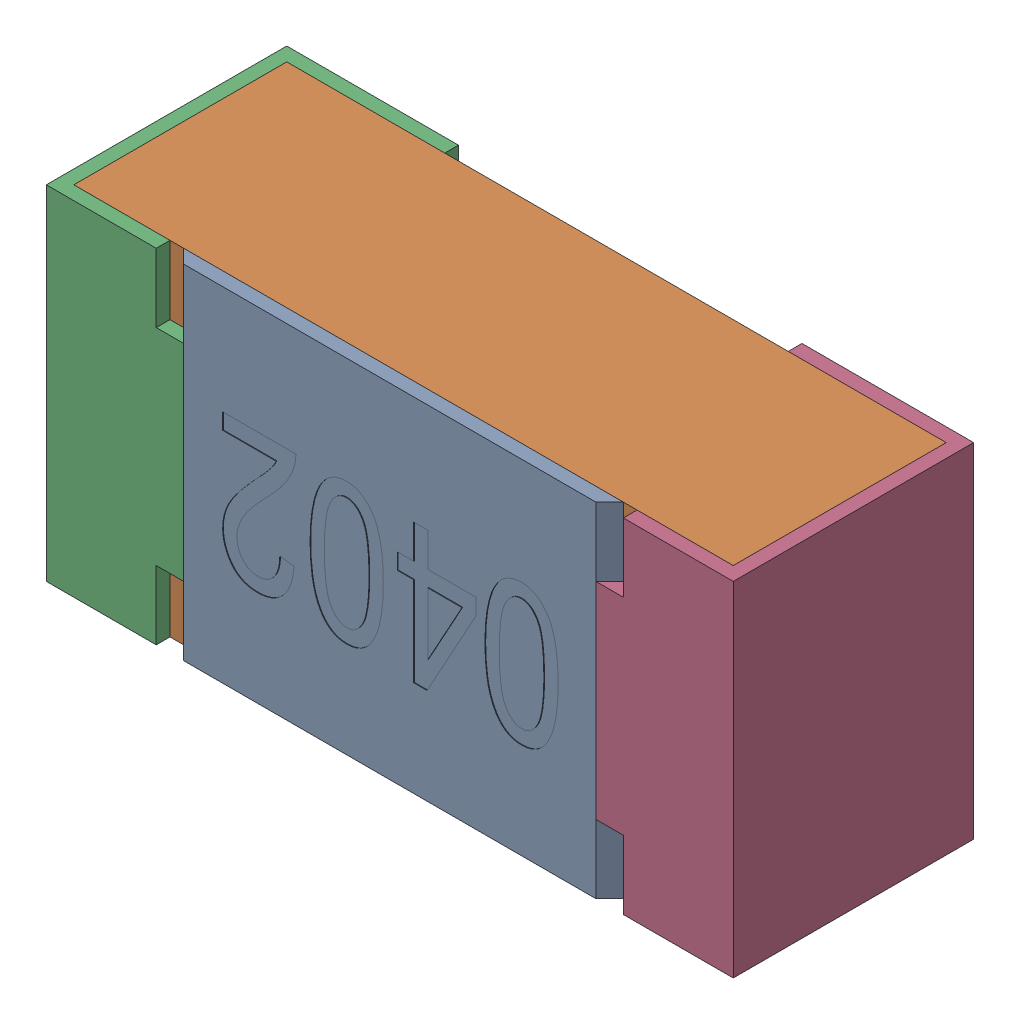
SolidWorks assembly R20, configuration Standard. Lengths in mm.
Overall size (1 0.5 0.35).
5 component instances, 4 part files, 0 mates.
Components (placement in the parent):
- R20-subassembly-1-1: R20-subassembly-1 [Standard] at (-10.0001 -17.9 0) x (-1 0 0) z (0 0 1) size (1 0.5 0.35)
  - User Library-R_0402-1: User Library-R_0402 [Standard] at origin size (0.64 0.5 0.02)
  - User Library-R_0402-1-1: User Library-R_0402-1 [Standard] at origin size (0.96 0.5 0.31)
  - User Library-R_0402-2-1: User Library-R_0402-2 [Standard] at origin size (0.25 0.5 0.35)
  - User Library-R_0402-3-1: User Library-R_0402-3 [Standard] at origin size (0.25 0.5 0.35)
